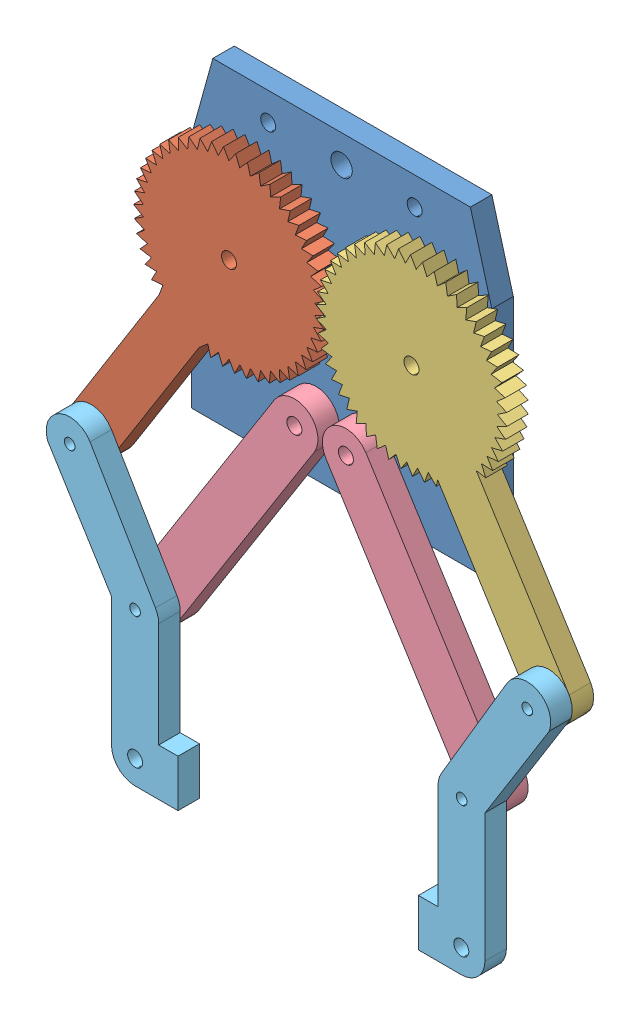
SolidWorks assembly Assem1, configuration Default. Lengths in mm.
Overall size (147.99 145.98 15).
7 component instances, 5 part files, 16 mates.
Components (placement in the parent):
- Part4-1: Part4 [Default] at (-261.118 -78.1778 287.232) size (70 73.03 5)
- Part1-1: Part1 [Default] at (-377.2071 135.9761 292.232) x (0.844695 -0.535248 0) z (0 0 1) size (44.43 87.75 5)
- Part1_2-1: Part1_2 [Default] at (30.936 -281.7893 292.232) x (0.869148 0.494552 0) z (0 0 1) size (44.42 87.69 5)
- Part2-1: Part2 [Default] at (-414.1686 21.6871 292.232) x (0.844695 -0.535248 0) z (0 0 1) size (11 71 5)
- Part2-2: Part2 [Default] at (44.8508 -386.8296 292.232) x (0.846397 0.532553 0) z (0 0 1) size (11 71 5)
- Part3-1: Part3 [Default] at (-168.5278 -257.9646 297.232) x (1 -0.000014 0) z (0 0 1) size (30.72 66.85 5)
- Part3-2: Part3 [Default] at (445.1797 -258.6642 302.232) x (-0.999998 0.002209 0) z (0 0 -1) size (30.72 66.85 5)
Mates (geometry in assembly coordinates):
- Parallel2: parallel anti-aligned: plane of Part4-1 through (-261.118 -78.1778 292.232) normal (0 0 1); plane of Part1-1 through (-377.2071 135.9761 292.232) normal (0 0 -1)
- Coincident10: coincident anti-aligned: plane of Part4-1 through (-261.118 -78.1778 292.232) normal (0 0 1); plane of Part1_2-1 through (30.936 -281.7893 292.232) normal (0 0 -1)
- Coincident11: coincident anti-aligned: plane of Part4-1 through (-261.118 -78.1778 292.232) normal (0 0 1); plane of Part2-1 through (100.7131 120.7226 292.232) normal (0 0 -1)
- Coincident12: coincident anti-aligned: plane of Part4-1 through (-261.118 -78.1778 292.232) normal (0 0 1); plane of Part2-2 through (176.7811 120.6205 292.232) normal (0 0 -1)
- Concentric30: concentric aligned: cylinder of Part4-1 through (117.6067 197.256 292.232) axis (0 0 -1) radius 1.75; cylinder of Part1-1 through (117.6067 197.256 297.232) axis (0 0 -1) radius 1.75
- Concentric31: concentric aligned: cylinder of Part4-1 through (160.1066 197.2221 292.232) axis (0 0 -1) radius 1.75; cylinder of Part1_2-1 through (160.1066 197.2221 297.232) axis (0 0 -1) radius 1.75
- Concentric32: concentric aligned: cylinder of Part4-1 through (144.8279 171.4043 292.232) axis (0 0 -1) radius 1.75; cylinder of Part2-2 through (144.8279 171.4043 297.232) axis (0 0 -1) radius 1.75
- Concentric33: concentric aligned: cylinder of Part4-1 through (132.8279 171.4043 292.232) axis (0 0 -1) radius 1.75; cylinder of Part2-1 through (132.8279 171.4043 297.232) axis (0 0 -1) radius 1.75
- Coincident15: coincident anti-aligned: plane of Part4-1 through (-261.118 -78.1778 292.232) normal (0 0 1); plane of Part1-1 through (-377.2071 135.9761 292.232) normal (0 0 -1)
- GearMate2: gear = 3.5 : 3.5 mm: circle of Part1-1; circle of Part1_2-1
- Coincident16: coincident anti-aligned: plane of Part1-1 through (-377.2071 135.9761 297.232) normal (0 0 1); plane of Part3-1 through (-168.5278 -257.9646 297.232) normal (0 0 -1)
- Concentric39: concentric aligned: cylinder of Part1-1 through (85.4918 146.5743 297.232) axis (0 0 -1) radius 1.25; cylinder of Part3-1 through (85.4918 146.5743 302.232) axis (0 0 -1) radius 1.25
- Concentric40: concentric aligned: cylinder of Part2-1 through (100.7131 120.7226 297.232) axis (0 0 -1) radius 1.25; cylinder of Part3-1 through (100.7131 120.7226 302.232) axis (0 0 -1) radius 1.25
- Coincident17: coincident anti-aligned: plane of Part2-2 through (176.7811 120.6205 297.232) normal (0 0 1); plane of Part3-2 through (445.1797 -258.6642 297.232) normal (0 0 -1)
- Concentric41: concentric anti-aligned: cylinder of Part2-2 through (176.7811 120.6205 297.232) axis (0 0 -1) radius 1.25; cylinder of Part3-2 through (176.7811 120.6205 297.232) axis (0 0 1) radius 1.25
- Concentric42: concentric anti-aligned: cylinder of Part1_2-1 through (192.0598 146.4383 297.232) axis (0 0 -1) radius 1.25; cylinder of Part3-2 through (192.0598 146.4383 297.232) axis (0 0 1) radius 1.25
